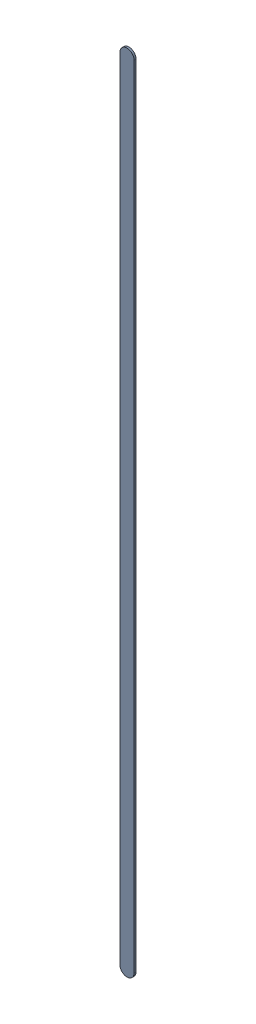
SolidWorks assembly Track (34.4mm,43.3mm)(34.4mm,57.5mm) on Top Layer, configuration Predeterminado. Lengths in mm.
Overall size (0.25 14.45 0.04).
2 component instances, 1 part files, 0 mates.
Components (placement in the parent):
- Track (34.4mm,43.3mm)(34.4mm,57.5mm) on Top Layer-1-1: Track (34.4mm,43.3mm)(34.4mm,57.5mm) on Top Layer-1 [Predeterminado] at (-68.317 -44.187 -0.0457) size (0.25 14.45 0.04)
  - Track (34.4mm,43.3mm)(34.4mm,57.5mm) on Top Layer-Part-1-1: Track (34.4mm,43.3mm)(34.4mm,57.5mm) on Top Layer-Part-1 [Predeterminado] at origin size (0.25 14.45 0.04)
